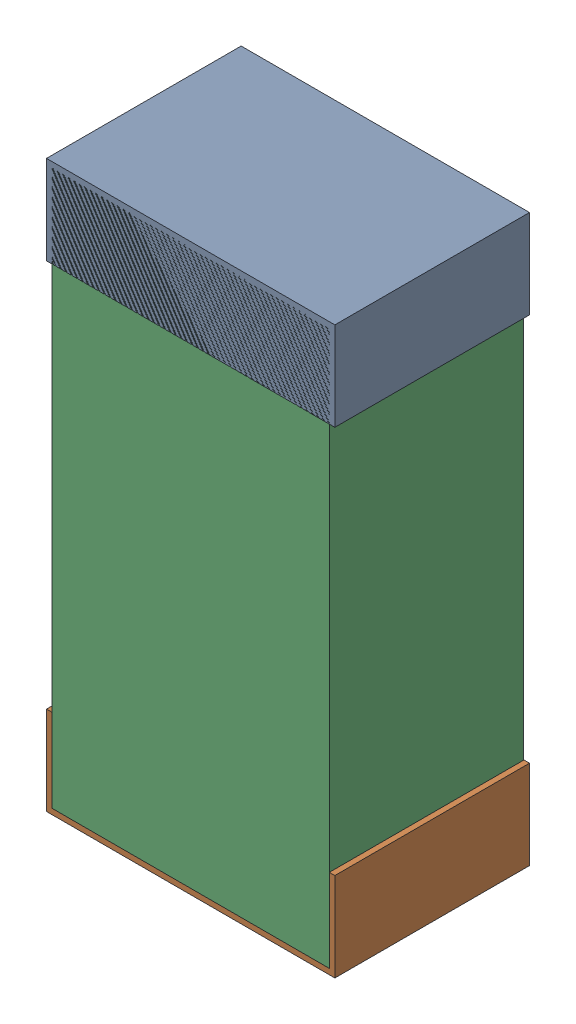
SolidWorks assembly C30, configuration Default. Lengths in mm.
Overall size (0.52 1.02 0.35).
6 component instances, 2 part files, 0 mates.
Components (placement in the parent):
- 870941120-1: 870941120 [Default] at (14.147 19.623 -1.9516) size (0.52 0.16 0.35)
  - Extruded_3-1: Extruded_3 [Default] at origin size (0.52 0.16 0.35)
- 870941120-2: 870941120 [Default] at (14.147 18.763 -1.9516) size (0.52 0.16 0.35)
  - Extruded_3-1: Extruded_3 [Default] at origin size (0.52 0.16 0.35)
- 870941280-1: 870941280 [Default] at (14.147 19.193 -1.9506) size (0.5 1 0.35)
  - Extruded_4-1: Extruded_4 [Default] at origin size (0.5 1 0.35)
